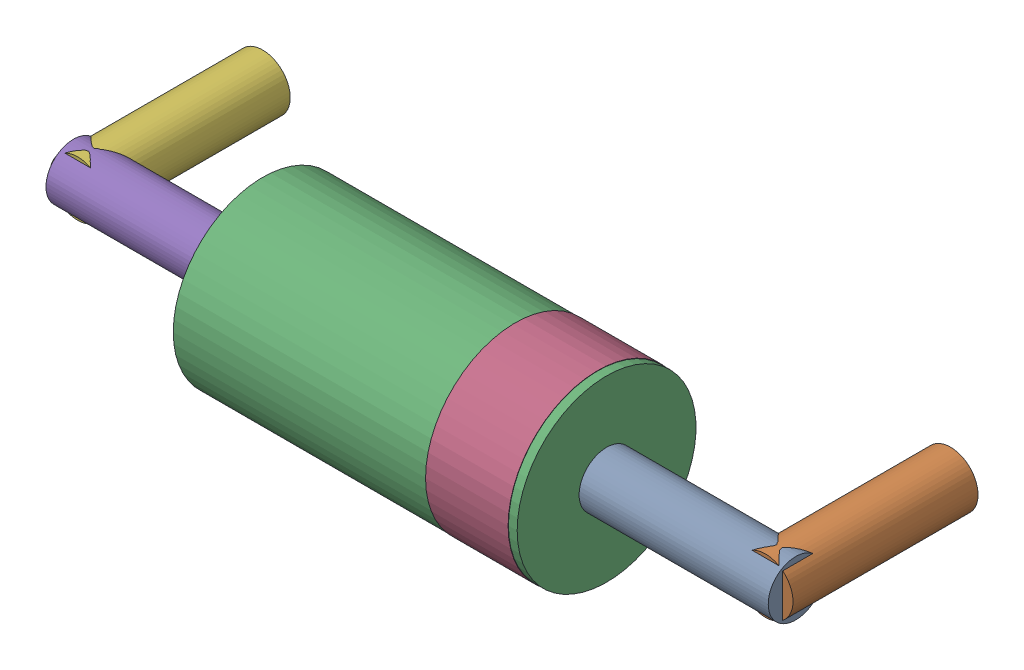
SolidWorks assembly D2, configuration Default. Lengths in mm.
Overall size (10.8 2.61 3.81).
12 component instances, 6 part files, 0 mates.
Components (placement in the parent):
- -1733042672-1: -1733042672 [Default] at (514.2502 261.9977 1.5) x (0 0 -1) z (-1 0 0) size (0.8 0.8 2.75)
  - Cylinder-1: Cylinder [Default] at origin size (0.8 0.8 2.75)
- -1733042992-1: -1733042992 [Default] at (513.9999 261.9999 -1) x (-1 0 0) z (0 0 1) size (0.8 0.8 2.69)
  - Cylinder_2-1: Cylinder_2 [Default] at origin size (0.8 0.8 2.69)
- -1733042432-1: -1733042432 [Default] at (511.5001 261.9975 1.5) x (0 0 -1) z (-1 0 0) size (2.6 2.6 5)
  - Cylinder_3-1: Cylinder_3 [Default] at origin size (2.6 2.6 5)
- -1733042152-1: -1733042152 [Default] at (511.3731 261.9976 1.5) x (0 0 -1) z (-1 0 0) size (2.61 2.61 1.2)
  - Cylinder_4-1: Cylinder_4 [Default] at origin size (2.61 2.61 1.2)
- -1733041072-1: -1733041072 [Default] at (503.7497 262.0023 1.5) x (0 0 -1) z (1 0 0) size (0.8 0.8 2.75)
  - Cylinder_5-1: Cylinder_5 [Default] at origin size (0.8 0.8 2.75)
- -1733041192-1: -1733041192 [Default] at (504.0001 262.0001 -1) x (1 0 0) z (0 0 1) size (0.8 0.8 2.69)
  - Cylinder_6-1: Cylinder_6 [Default] at origin size (0.8 0.8 2.69)
